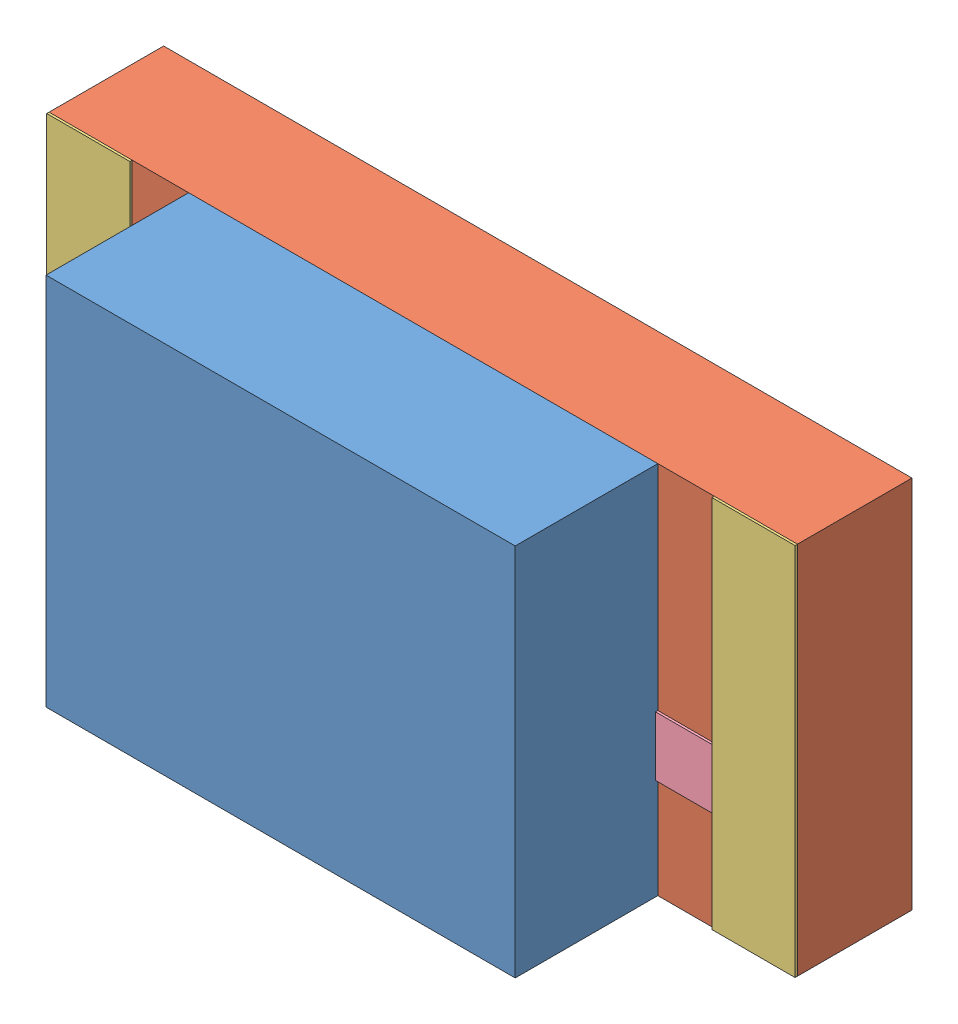
SolidWorks assembly User Library-LED1206R, configuration Default. Lengths in mm.
Overall size (3.2 1.6 1.52).
14 component instances, 6 part files, 0 mates.
Components (placement in the parent):
- User Library-LED1206R_Open CASCADE STEP translator 6.2 278.2-1: User Library-LED1206R_Open CASCADE STEP translator 6.2 278.2 [Default] at origin size (3.2 1.6 1.1)
  - User Library-LED1206R_352701008-1: User Library-LED1206R_352701008 [Default] at (1.524 0.0127 0.5027) size (2.01 1.6 0.61)
    - User Library-LED1206R_Extruded2-1: User Library-LED1206R_Extruded2 [Default] at origin size (2.01 1.6 0.61)
  - User Library-LED1206R_352697936-1: User Library-LED1206R_352697936 [Default] at (1.524 0.0127 0.0127) size (3.2 1.6 0.49)
    - User Library-LED1206R_Extruded1-1: User Library-LED1206R_Extruded1 [Default] at origin size (3.2 1.6 0.49)
  - User Library-LED1206R_352697808-1: User Library-LED1206R_352697808 [Default] at (2.9464 0.0127 0.5027) size (0.36 1.6 0.01)
    - User Library-LED1206R_Extruded-1: User Library-LED1206R_Extruded [Default] at origin size (0.36 1.6 0.01)
  - User Library-LED1206R_352697808-2: User Library-LED1206R_352697808 [Default] at (0.1016 0.0127 0.5027) size (0.36 1.6 0.01)
    - User Library-LED1206R_Extruded-1: User Library-LED1206R_Extruded [Default] at origin size (0.36 1.6 0.01)
  - User Library-LED1206R_352698192-1: User Library-LED1206R_352698192 [Default] at (2.1971 0.0254 0.5027) size (1.14 0.76 0.01)
    - User Library-LED1206R_Extruded4-1: User Library-LED1206R_Extruded4 [Default] at origin size (1.14 0.76 0.01)
  - User Library-LED1206R_352699472-1: User Library-LED1206R_352699472 [Default] at (0.6096 0.0254 0.5027) size (0.65 0.76 0.01)
    - User Library-LED1206R_Extruded3-1: User Library-LED1206R_Extruded3 [Default] at origin size (0.65 0.76 0.01)
- User Library-LED1206R_Board-1: User Library-LED1206R_Board [Default] at (0 0 -0.4039) size (0.03 0.03 0.42)
